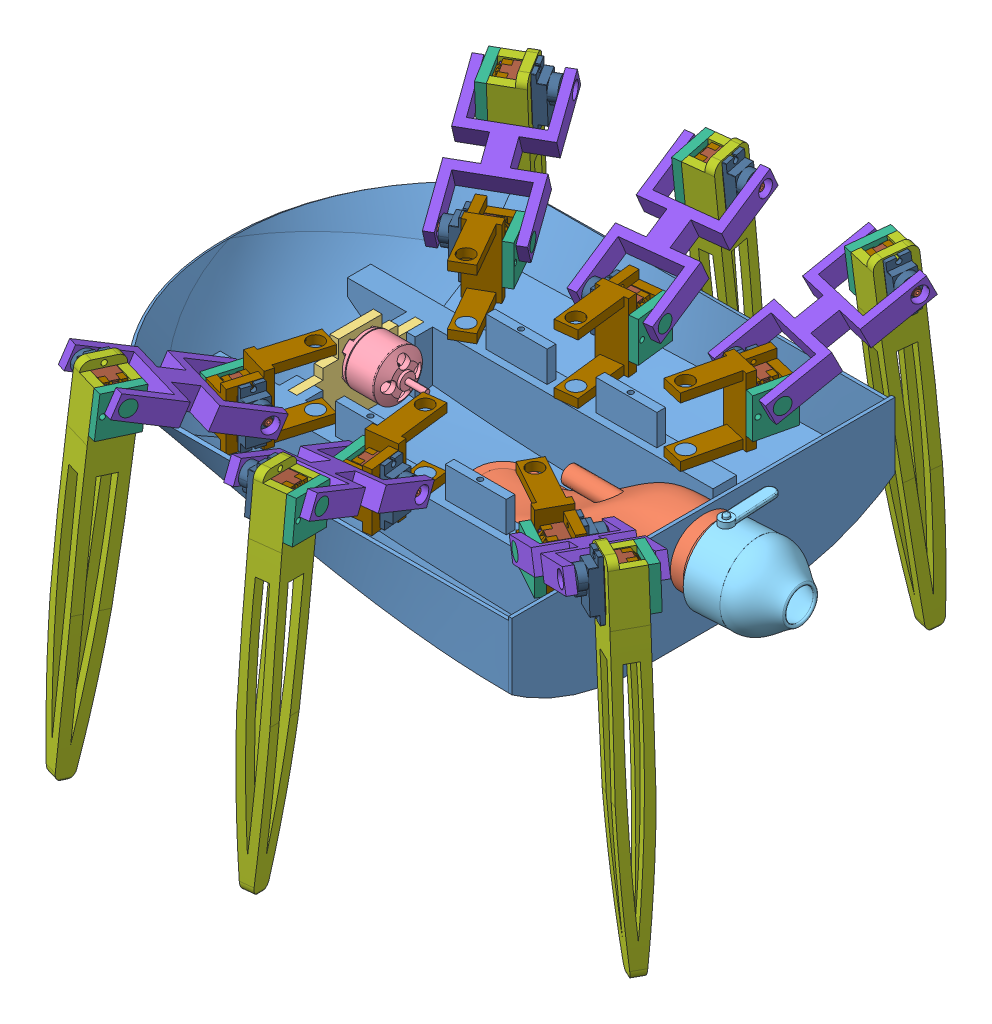
SolidWorks assembly TurbineCoverAssemble, configuration Default. Lengths in mm.
Overall size (353.16 206.26 356.62).
294 component instances, 27 part files, 17 mates.
Components (placement in the parent):
- BottonCover-1: BottonCover [Default] at (202.224 140.7704 163.9757) size (277.71 67.81 225.14)
- Turbine sketch-1: Turbine sketch [Default] at (187.224 85.7703 163.9757) x (0.000008 -1 0) z (1 0.000008 0) size (64 54 170.85)
- MotorBaseAssemble-1: MotorBaseAssemble [Default] at (-58.3893 121.5175 203.7657) x (0 -1 0) z (1 0 0) size (43.76 73 43.4)
  - motorBase-1: motorBase [Default] at (16.3885 39.79 60.6133) size (43.4 73 5)
  - Motor_BLDC_2212,6T_2200KV-1: Motor_BLDC_2212,6T_2200KV [Default] at (0.7745 39.79 64.0133) x (1 0 0) z (0 -1 0) size (27.9 40 27.9)
- Turbine Steering-2: Turbine Steering [Default] at (233.1876 119.5531 162.7395) x (-0.998386 -0.000008 0.056796) z (-0.056796 0 -0.998386) size (44.47 54 52.58)
- Leg assamble-1: Leg assamble [Default] at (-57.4595 156.272 55.9898) x (-0.493863 0.112847 -0.862186) z (0.867729 0 -0.497038) size (123.73 200 44.3)
  - CoverLeg-1: CoverLeg [Default] at (5.4977 12.0108 18.4868) size (22.4 22.9 10)
  - LowLeg-1: LowLeg [Default] at (5.4977 12.0108 35.7868) size (22.4 200 18.22)
  - JoinLeg-1: JoinLeg [Default] at (-21.7924 8.0579 35.6368) x (0 0 -1) z (0.947571 0.319544 0) size (44.3 12.4 85)
  - CoverLeg-3: CoverLeg [Default] at (-63.8885 -11.1546 52.7868) x (-0.993612 0.112847 0) z (0 0 -1) size (22.4 22.9 10)
  - MG90S-1: MG90S [Default] at (-15.7901 -20.7716 66.5373) x (1 0 0) z (0 -1 0) size (13.58 32.57 32)
    - MG90S.STEP-1: MG90S.STEP [Default] at origin size (13.58 32.57 32)
      - Part1.STEP-1: Part1.STEP [Default] at (21.0878 -43.0505 -32.5824) x (0 0 -1) z (1 0 0) size (22.54 9.07 12)
      - Part2.STEP-1: Part2.STEP [Default] at (21.0878 -25.5505 -32.5824) x (0 0 -1) z (1 0 0) size (32 13 12)
      - Part3.STEP-1: Part3.STEP [Default] at (21.0878 -36.0505 -32.5824) x (0 0 -1) z (1 0 0) size (22.5 16 12)
      - spur gear_iso_ISO - Spur gear 0.25M 38T 20PA 1.5FW ---S38A75H50L1.5N.STEP-1: spur gear_iso_ISO - Spur gear 0.25M 38T 20PA 1.5FW ---S38A75H50L1.5N.STEP [Default] at (21.0878 -22.3005 -37.8324) x (0 -1 0) z (0.87496 0 0.484196) size (1.5 9.98 10)
      - spur gear_iso_ISO - Spur gear 0.3M 31T 20PA 2FW ---S31A75H50L1.25N.STEP-1: spur gear_iso_ISO - Spur gear 0.3M 31T 20PA 2FW ---S31A75H50L1.25N.STEP [Default] at (21.0878 -19.8005 -31.3324) x (0 -1 0) z (0.109568 0 -0.993979) size (2 9.88 9.89)
      - spur gear_iso_ISO - Spur gear 0.4M 23T 20PA 2.75FW ---S23A75H50L1.5N.STEP-1: spur gear_iso_ISO - Spur gear 0.4M 23T 20PA 2.75FW ---S23A75H50L1.5N.STEP [Default] at (21.0878 -19.8005 -37.8324) x (0 1 0) z (-0.993238 0 0.116099) size (2.75 9.97 9.99)
      - spur gear_iso_ISO - Spur gear 0.25M 31T 20PA 1.25FW ---S31A75H50L1.25N.STEP-1: spur gear_iso_ISO - Spur gear 0.25M 31T 20PA 1.25FW ---S31A75H50L1.25N.STEP [Default] at (21.0878 -25.0505 -31.3324) x (0 1 0) z (0.977188 0 0.212376) size (1.25 8.24 8.25)
      - spur gear_iso_ISO - Spur gear 0.25M 10T 20PA 2FW ---S10A75H50L1.25N.STEP-1: spur gear_iso_ISO - Spur gear 0.25M 10T 20PA 2FW ---S10A75H50L1.25N.STEP [Default] at (21.0878 -23.8005 -31.3324) x (0 1 0) z (0.977188 0 0.212376) size (2 2.87 3)
      - gear3.STEP-1: gear3.STEP [Default] at (21.0878 -22.3005 -37.8324) x (0.87496 0 0.484196) z (-0.484196 0 0.87496) size (3.98 2.5 3.92)
      - gear1.STEP-1: gear1.STEP [Default] at (21.0878 -19.8005 -31.3324) x (0.109568 0 -0.993979) z (0.993979 0 0.109568) size (3.96 2.5 3.87)
      - gear2.STEP-1: gear2.STEP [Default] at (21.0878 -26.3005 -26.3324) x (0.891105 0 -0.453797) z (0.453797 0 0.891105) size (2.5 2.5 2.5)
      - Part4.STEP-1: Part4.STEP [Default] at (21.0878 -17.0505 -37.8324) x (0.993238 0 -0.116099) z (0.116099 0 0.993238) size (4.5 6.5 4.5)
      - Motor_Body.STEP-1: Motor_Body.STEP [Default] at (21.0878 -26.5505 -26.3324) x (-1 0 0) z (0 0 1) size (10 14.25 8)
      - Motor_Body2.STEP-1: Motor_Body2.STEP [Default] at (21.0878 -39.0505 -26.3324) size (10 2 8)
      - cilinder2.STEP-1: cilinder2.STEP [Default] at (21.0878 -31.8005 -37.8324) x (0.116099 0 0.993238) z (-0.993238 0 0.116099) size (1.5 15 1.5)
      - cilinder1.STEP-1: cilinder1.STEP [Default] at (21.0878 -27.3005 -31.3324) x (0.109568 0 -0.993979) z (0.993979 0 0.109568) size (1.25 12 1.25)
      - Part5.STEP-1: Part5.STEP [Default] at (21.0878 -40.0505 -32.0824) x (0 0 -1) z (1 0 0) size (19.28 16 10.15)
      - Part6.STEP-1: Part6.STEP [Default] at (16.5878 -42.0505 -22.8324) size (1.5 21 1.5)
      - Part6.STEP-2: Part6.STEP [Default] at (25.5878 -40.5505 -42.3324) size (1.5 21 1.5)
  - MG90S-2: MG90S [Default] at (-46.7884 -45.6872 4.9363) x (-0.993612 0.112847 0) z (-0.112847 -0.993612 0) size (13.58 32.57 32)
    - MG90S.STEP-1: MG90S.STEP [Default] at origin size (13.58 32.57 32)
      - Part1.STEP-1: Part1.STEP [Default] at (21.0878 -43.0505 -32.5824) x (0 0 -1) z (1 0 0) size (22.54 9.07 12)
      - Part2.STEP-1: Part2.STEP [Default] at (21.0878 -25.5505 -32.5824) x (0 0 -1) z (1 0 0) size (32 13 12)
      - Part3.STEP-1: Part3.STEP [Default] at (21.0878 -36.0505 -32.5824) x (0 0 -1) z (1 0 0) size (22.5 16 12)
      - spur gear_iso_ISO - Spur gear 0.25M 38T 20PA 1.5FW ---S38A75H50L1.5N.STEP-1: spur gear_iso_ISO - Spur gear 0.25M 38T 20PA 1.5FW ---S38A75H50L1.5N.STEP [Default] at (21.0878 -22.3005 -37.8324) x (0 -1 0) z (0.87496 0 0.484196) size (1.5 9.98 10)
      - spur gear_iso_ISO - Spur gear 0.3M 31T 20PA 2FW ---S31A75H50L1.25N.STEP-1: spur gear_iso_ISO - Spur gear 0.3M 31T 20PA 2FW ---S31A75H50L1.25N.STEP [Default] at (21.0878 -19.8005 -31.3324) x (0 -1 0) z (0.109568 0 -0.993979) size (2 9.88 9.89)
      - spur gear_iso_ISO - Spur gear 0.4M 23T 20PA 2.75FW ---S23A75H50L1.5N.STEP-1: spur gear_iso_ISO - Spur gear 0.4M 23T 20PA 2.75FW ---S23A75H50L1.5N.STEP [Default] at (21.0878 -19.8005 -37.8324) x (0 1 0) z (-0.993238 0 0.116099) size (2.75 9.97 9.99)
      - spur gear_iso_ISO - Spur gear 0.25M 31T 20PA 1.25FW ---S31A75H50L1.25N.STEP-1: spur gear_iso_ISO - Spur gear 0.25M 31T 20PA 1.25FW ---S31A75H50L1.25N.STEP [Default] at (21.0878 -25.0505 -31.3324) x (0 1 0) z (0.977188 0 0.212376) size (1.25 8.24 8.25)
      - spur gear_iso_ISO - Spur gear 0.25M 10T 20PA 2FW ---S10A75H50L1.25N.STEP-1: spur gear_iso_ISO - Spur gear 0.25M 10T 20PA 2FW ---S10A75H50L1.25N.STEP [Default] at (21.0878 -23.8005 -31.3324) x (0 1 0) z (0.977188 0 0.212376) size (2 2.87 3)
      - gear3.STEP-1: gear3.STEP [Default] at (21.0878 -22.3005 -37.8324) x (0.87496 0 0.484196) z (-0.484196 0 0.87496) size (3.98 2.5 3.92)
      - gear1.STEP-1: gear1.STEP [Default] at (21.0878 -19.8005 -31.3324) x (0.109568 0 -0.993979) z (0.993979 0 0.109568) size (3.96 2.5 3.87)
      - gear2.STEP-1: gear2.STEP [Default] at (21.0878 -26.3005 -26.3324) x (0.891105 0 -0.453797) z (0.453797 0 0.891105) size (2.5 2.5 2.5)
      - Part4.STEP-1: Part4.STEP [Default] at (21.0878 -17.0505 -37.8324) x (0.993238 0 -0.116099) z (0.116099 0 0.993238) size (4.5 6.5 4.5)
      - Motor_Body.STEP-1: Motor_Body.STEP [Default] at (21.0878 -26.5505 -26.3324) x (-1 0 0) z (0 0 1) size (10 14.25 8)
      - Motor_Body2.STEP-1: Motor_Body2.STEP [Default] at (21.0878 -39.0505 -26.3324) size (10 2 8)
      - cilinder2.STEP-1: cilinder2.STEP [Default] at (21.0878 -31.8005 -37.8324) x (0.116099 0 0.993238) z (-0.993238 0 0.116099) size (1.5 15 1.5)
      - cilinder1.STEP-1: cilinder1.STEP [Default] at (21.0878 -27.3005 -31.3324) x (0.109568 0 -0.993979) z (0.993979 0 0.109568) size (1.25 12 1.25)
      - Part5.STEP-1: Part5.STEP [Default] at (21.0878 -40.0505 -32.0824) x (0 0 -1) z (1 0 0) size (19.28 16 10.15)
      - Part6.STEP-1: Part6.STEP [Default] at (16.5878 -42.0505 -22.8324) size (1.5 21 1.5)
      - Part6.STEP-2: Part6.STEP [Default] at (25.5878 -40.5505 -42.3324) size (1.5 21 1.5)
  - JointChassis-4: JointChassis [Default] at (-63.8885 -11.1546 30.4868) x (-0.112847 -0.993612 0) z (0 0 1) size (39.1 52.4 17.3)
- Leg assamble-2: Leg assamble [Default] at (37.6165 156.272 28.8883) x (-0.115049 0.112847 -0.986929) z (0.993274 0 -0.115788) size (123.73 200 44.3)
  - CoverLeg-1: CoverLeg [Default] at (5.4977 12.0108 18.4868) size (22.4 22.9 10)
  - LowLeg-1: LowLeg [Default] at (5.4977 12.0108 35.7868) size (22.4 200 18.22)
  - JoinLeg-1: JoinLeg [Default] at (-21.7924 8.0579 35.6368) x (0 0 -1) z (0.947571 0.319544 0) size (44.3 12.4 85)
  - CoverLeg-3: CoverLeg [Default] at (-63.8885 -11.1546 52.7868) x (-0.993612 0.112847 0) z (0 0 -1) size (22.4 22.9 10)
  - MG90S-1: MG90S [Default] at (-15.7901 -20.7716 66.5373) x (1 0 0) z (0 -1 0) size (13.58 32.57 32)
    - MG90S.STEP-1: MG90S.STEP [Default] at origin size (13.58 32.57 32)
      - Part1.STEP-1: Part1.STEP [Default] at (21.0878 -43.0505 -32.5824) x (0 0 -1) z (1 0 0) size (22.54 9.07 12)
      - Part2.STEP-1: Part2.STEP [Default] at (21.0878 -25.5505 -32.5824) x (0 0 -1) z (1 0 0) size (32 13 12)
      - Part3.STEP-1: Part3.STEP [Default] at (21.0878 -36.0505 -32.5824) x (0 0 -1) z (1 0 0) size (22.5 16 12)
      - spur gear_iso_ISO - Spur gear 0.25M 38T 20PA 1.5FW ---S38A75H50L1.5N.STEP-1: spur gear_iso_ISO - Spur gear 0.25M 38T 20PA 1.5FW ---S38A75H50L1.5N.STEP [Default] at (21.0878 -22.3005 -37.8324) x (0 -1 0) z (0.87496 0 0.484196) size (1.5 9.98 10)
      - spur gear_iso_ISO - Spur gear 0.3M 31T 20PA 2FW ---S31A75H50L1.25N.STEP-1: spur gear_iso_ISO - Spur gear 0.3M 31T 20PA 2FW ---S31A75H50L1.25N.STEP [Default] at (21.0878 -19.8005 -31.3324) x (0 -1 0) z (0.109568 0 -0.993979) size (2 9.88 9.89)
      - spur gear_iso_ISO - Spur gear 0.4M 23T 20PA 2.75FW ---S23A75H50L1.5N.STEP-1: spur gear_iso_ISO - Spur gear 0.4M 23T 20PA 2.75FW ---S23A75H50L1.5N.STEP [Default] at (21.0878 -19.8005 -37.8324) x (0 1 0) z (-0.993238 0 0.116099) size (2.75 9.97 9.99)
      - spur gear_iso_ISO - Spur gear 0.25M 31T 20PA 1.25FW ---S31A75H50L1.25N.STEP-1: spur gear_iso_ISO - Spur gear 0.25M 31T 20PA 1.25FW ---S31A75H50L1.25N.STEP [Default] at (21.0878 -25.0505 -31.3324) x (0 1 0) z (0.977188 0 0.212376) size (1.25 8.24 8.25)
      - spur gear_iso_ISO - Spur gear 0.25M 10T 20PA 2FW ---S10A75H50L1.25N.STEP-1: spur gear_iso_ISO - Spur gear 0.25M 10T 20PA 2FW ---S10A75H50L1.25N.STEP [Default] at (21.0878 -23.8005 -31.3324) x (0 1 0) z (0.977188 0 0.212376) size (2 2.87 3)
      - gear3.STEP-1: gear3.STEP [Default] at (21.0878 -22.3005 -37.8324) x (0.87496 0 0.484196) z (-0.484196 0 0.87496) size (3.98 2.5 3.92)
      - gear1.STEP-1: gear1.STEP [Default] at (21.0878 -19.8005 -31.3324) x (0.109568 0 -0.993979) z (0.993979 0 0.109568) size (3.96 2.5 3.87)
      - gear2.STEP-1: gear2.STEP [Default] at (21.0878 -26.3005 -26.3324) x (0.891105 0 -0.453797) z (0.453797 0 0.891105) size (2.5 2.5 2.5)
      - Part4.STEP-1: Part4.STEP [Default] at (21.0878 -17.0505 -37.8324) x (0.993238 0 -0.116099) z (0.116099 0 0.993238) size (4.5 6.5 4.5)
      - Motor_Body.STEP-1: Motor_Body.STEP [Default] at (21.0878 -26.5505 -26.3324) x (-1 0 0) z (0 0 1) size (10 14.25 8)
      - Motor_Body2.STEP-1: Motor_Body2.STEP [Default] at (21.0878 -39.0505 -26.3324) size (10 2 8)
      - cilinder2.STEP-1: cilinder2.STEP [Default] at (21.0878 -31.8005 -37.8324) x (0.116099 0 0.993238) z (-0.993238 0 0.116099) size (1.5 15 1.5)
      - cilinder1.STEP-1: cilinder1.STEP [Default] at (21.0878 -27.3005 -31.3324) x (0.109568 0 -0.993979) z (0.993979 0 0.109568) size (1.25 12 1.25)
      - Part5.STEP-1: Part5.STEP [Default] at (21.0878 -40.0505 -32.0824) x (0 0 -1) z (1 0 0) size (19.28 16 10.15)
      - Part6.STEP-1: Part6.STEP [Default] at (16.5878 -42.0505 -22.8324) size (1.5 21 1.5)
      - Part6.STEP-2: Part6.STEP [Default] at (25.5878 -40.5505 -42.3324) size (1.5 21 1.5)
  - MG90S-2: MG90S [Default] at (-46.7884 -45.6872 4.9363) x (-0.993612 0.112847 0) z (-0.112847 -0.993612 0) size (13.58 32.57 32)
    - MG90S.STEP-1: MG90S.STEP [Default] at origin size (13.58 32.57 32)
      - Part1.STEP-1: Part1.STEP [Default] at (21.0878 -43.0505 -32.5824) x (0 0 -1) z (1 0 0) size (22.54 9.07 12)
      - Part2.STEP-1: Part2.STEP [Default] at (21.0878 -25.5505 -32.5824) x (0 0 -1) z (1 0 0) size (32 13 12)
      - Part3.STEP-1: Part3.STEP [Default] at (21.0878 -36.0505 -32.5824) x (0 0 -1) z (1 0 0) size (22.5 16 12)
      - spur gear_iso_ISO - Spur gear 0.25M 38T 20PA 1.5FW ---S38A75H50L1.5N.STEP-1: spur gear_iso_ISO - Spur gear 0.25M 38T 20PA 1.5FW ---S38A75H50L1.5N.STEP [Default] at (21.0878 -22.3005 -37.8324) x (0 -1 0) z (0.87496 0 0.484196) size (1.5 9.98 10)
      - spur gear_iso_ISO - Spur gear 0.3M 31T 20PA 2FW ---S31A75H50L1.25N.STEP-1: spur gear_iso_ISO - Spur gear 0.3M 31T 20PA 2FW ---S31A75H50L1.25N.STEP [Default] at (21.0878 -19.8005 -31.3324) x (0 -1 0) z (0.109568 0 -0.993979) size (2 9.88 9.89)
      - spur gear_iso_ISO - Spur gear 0.4M 23T 20PA 2.75FW ---S23A75H50L1.5N.STEP-1: spur gear_iso_ISO - Spur gear 0.4M 23T 20PA 2.75FW ---S23A75H50L1.5N.STEP [Default] at (21.0878 -19.8005 -37.8324) x (0 1 0) z (-0.993238 0 0.116099) size (2.75 9.97 9.99)
      - spur gear_iso_ISO - Spur gear 0.25M 31T 20PA 1.25FW ---S31A75H50L1.25N.STEP-1: spur gear_iso_ISO - Spur gear 0.25M 31T 20PA 1.25FW ---S31A75H50L1.25N.STEP [Default] at (21.0878 -25.0505 -31.3324) x (0 1 0) z (0.977188 0 0.212376) size (1.25 8.24 8.25)
      - spur gear_iso_ISO - Spur gear 0.25M 10T 20PA 2FW ---S10A75H50L1.25N.STEP-1: spur gear_iso_ISO - Spur gear 0.25M 10T 20PA 2FW ---S10A75H50L1.25N.STEP [Default] at (21.0878 -23.8005 -31.3324) x (0 1 0) z (0.977188 0 0.212376) size (2 2.87 3)
      - gear3.STEP-1: gear3.STEP [Default] at (21.0878 -22.3005 -37.8324) x (0.87496 0 0.484196) z (-0.484196 0 0.87496) size (3.98 2.5 3.92)
      - gear1.STEP-1: gear1.STEP [Default] at (21.0878 -19.8005 -31.3324) x (0.109568 0 -0.993979) z (0.993979 0 0.109568) size (3.96 2.5 3.87)
      - gear2.STEP-1: gear2.STEP [Default] at (21.0878 -26.3005 -26.3324) x (0.891105 0 -0.453797) z (0.453797 0 0.891105) size (2.5 2.5 2.5)
      - Part4.STEP-1: Part4.STEP [Default] at (21.0878 -17.0505 -37.8324) x (0.993238 0 -0.116099) z (0.116099 0 0.993238) size (4.5 6.5 4.5)
      - Motor_Body.STEP-1: Motor_Body.STEP [Default] at (21.0878 -26.5505 -26.3324) x (-1 0 0) z (0 0 1) size (10 14.25 8)
      - Motor_Body2.STEP-1: Motor_Body2.STEP [Default] at (21.0878 -39.0505 -26.3324) size (10 2 8)
      - cilinder2.STEP-1: cilinder2.STEP [Default] at (21.0878 -31.8005 -37.8324) x (0.116099 0 0.993238) z (-0.993238 0 0.116099) size (1.5 15 1.5)
      - cilinder1.STEP-1: cilinder1.STEP [Default] at (21.0878 -27.3005 -31.3324) x (0.109568 0 -0.993979) z (0.993979 0 0.109568) size (1.25 12 1.25)
      - Part5.STEP-1: Part5.STEP [Default] at (21.0878 -40.0505 -32.0824) x (0 0 -1) z (1 0 0) size (19.28 16 10.15)
      - Part6.STEP-1: Part6.STEP [Default] at (16.5878 -42.0505 -22.8324) size (1.5 21 1.5)
      - Part6.STEP-2: Part6.STEP [Default] at (25.5878 -40.5505 -42.3324) size (1.5 21 1.5)
  - JointChassis-4: JointChassis [Default] at (-63.8885 -11.1546 30.4868) x (-0.112847 -0.993612 0) z (0 0 1) size (39.1 52.4 17.3)
- Leg assamble-3: Leg assamble [Default] at (134.6264 156.272 17.3538) x (0.22549 0.112847 -0.967688) z (0.973909 0 0.226939) size (123.73 200 44.3)
  - CoverLeg-1: CoverLeg [Default] at (5.4977 12.0108 18.4868) size (22.4 22.9 10)
  - LowLeg-1: LowLeg [Default] at (5.4977 12.0108 35.7868) size (22.4 200 18.22)
  - JoinLeg-1: JoinLeg [Default] at (-21.7924 8.0579 35.6368) x (0 0 -1) z (0.947571 0.319544 0) size (44.3 12.4 85)
  - CoverLeg-3: CoverLeg [Default] at (-63.8885 -11.1546 52.7868) x (-0.993612 0.112847 0) z (0 0 -1) size (22.4 22.9 10)
  - MG90S-1: MG90S [Default] at (-15.7901 -20.7716 66.5373) x (1 0 0) z (0 -1 0) size (13.58 32.57 32)
    - MG90S.STEP-1: MG90S.STEP [Default] at origin size (13.58 32.57 32)
      - Part1.STEP-1: Part1.STEP [Default] at (21.0878 -43.0505 -32.5824) x (0 0 -1) z (1 0 0) size (22.54 9.07 12)
      - Part2.STEP-1: Part2.STEP [Default] at (21.0878 -25.5505 -32.5824) x (0 0 -1) z (1 0 0) size (32 13 12)
      - Part3.STEP-1: Part3.STEP [Default] at (21.0878 -36.0505 -32.5824) x (0 0 -1) z (1 0 0) size (22.5 16 12)
      - spur gear_iso_ISO - Spur gear 0.25M 38T 20PA 1.5FW ---S38A75H50L1.5N.STEP-1: spur gear_iso_ISO - Spur gear 0.25M 38T 20PA 1.5FW ---S38A75H50L1.5N.STEP [Default] at (21.0878 -22.3005 -37.8324) x (0 -1 0) z (0.87496 0 0.484196) size (1.5 9.98 10)
      - spur gear_iso_ISO - Spur gear 0.3M 31T 20PA 2FW ---S31A75H50L1.25N.STEP-1: spur gear_iso_ISO - Spur gear 0.3M 31T 20PA 2FW ---S31A75H50L1.25N.STEP [Default] at (21.0878 -19.8005 -31.3324) x (0 -1 0) z (0.109568 0 -0.993979) size (2 9.88 9.89)
      - spur gear_iso_ISO - Spur gear 0.4M 23T 20PA 2.75FW ---S23A75H50L1.5N.STEP-1: spur gear_iso_ISO - Spur gear 0.4M 23T 20PA 2.75FW ---S23A75H50L1.5N.STEP [Default] at (21.0878 -19.8005 -37.8324) x (0 1 0) z (-0.993238 0 0.116099) size (2.75 9.97 9.99)
      - spur gear_iso_ISO - Spur gear 0.25M 31T 20PA 1.25FW ---S31A75H50L1.25N.STEP-1: spur gear_iso_ISO - Spur gear 0.25M 31T 20PA 1.25FW ---S31A75H50L1.25N.STEP [Default] at (21.0878 -25.0505 -31.3324) x (0 1 0) z (0.977188 0 0.212376) size (1.25 8.24 8.25)
      - spur gear_iso_ISO - Spur gear 0.25M 10T 20PA 2FW ---S10A75H50L1.25N.STEP-1: spur gear_iso_ISO - Spur gear 0.25M 10T 20PA 2FW ---S10A75H50L1.25N.STEP [Default] at (21.0878 -23.8005 -31.3324) x (0 1 0) z (0.977188 0 0.212376) size (2 2.87 3)
      - gear3.STEP-1: gear3.STEP [Default] at (21.0878 -22.3005 -37.8324) x (0.87496 0 0.484196) z (-0.484196 0 0.87496) size (3.98 2.5 3.92)
      - gear1.STEP-1: gear1.STEP [Default] at (21.0878 -19.8005 -31.3324) x (0.109568 0 -0.993979) z (0.993979 0 0.109568) size (3.96 2.5 3.87)
      - gear2.STEP-1: gear2.STEP [Default] at (21.0878 -26.3005 -26.3324) x (0.891105 0 -0.453797) z (0.453797 0 0.891105) size (2.5 2.5 2.5)
      - Part4.STEP-1: Part4.STEP [Default] at (21.0878 -17.0505 -37.8324) x (0.993238 0 -0.116099) z (0.116099 0 0.993238) size (4.5 6.5 4.5)
      - Motor_Body.STEP-1: Motor_Body.STEP [Default] at (21.0878 -26.5505 -26.3324) x (-1 0 0) z (0 0 1) size (10 14.25 8)
      - Motor_Body2.STEP-1: Motor_Body2.STEP [Default] at (21.0878 -39.0505 -26.3324) size (10 2 8)
      - cilinder2.STEP-1: cilinder2.STEP [Default] at (21.0878 -31.8005 -37.8324) x (0.116099 0 0.993238) z (-0.993238 0 0.116099) size (1.5 15 1.5)
      - cilinder1.STEP-1: cilinder1.STEP [Default] at (21.0878 -27.3005 -31.3324) x (0.109568 0 -0.993979) z (0.993979 0 0.109568) size (1.25 12 1.25)
      - Part5.STEP-1: Part5.STEP [Default] at (21.0878 -40.0505 -32.0824) x (0 0 -1) z (1 0 0) size (19.28 16 10.15)
      - Part6.STEP-1: Part6.STEP [Default] at (16.5878 -42.0505 -22.8324) size (1.5 21 1.5)
      - Part6.STEP-2: Part6.STEP [Default] at (25.5878 -40.5505 -42.3324) size (1.5 21 1.5)
  - MG90S-2: MG90S [Default] at (-46.7884 -45.6872 4.9363) x (-0.993612 0.112847 0) z (-0.112847 -0.993612 0) size (13.58 32.57 32)
    - MG90S.STEP-1: MG90S.STEP [Default] at origin size (13.58 32.57 32)
      - Part1.STEP-1: Part1.STEP [Default] at (21.0878 -43.0505 -32.5824) x (0 0 -1) z (1 0 0) size (22.54 9.07 12)
      - Part2.STEP-1: Part2.STEP [Default] at (21.0878 -25.5505 -32.5824) x (0 0 -1) z (1 0 0) size (32 13 12)
      - Part3.STEP-1: Part3.STEP [Default] at (21.0878 -36.0505 -32.5824) x (0 0 -1) z (1 0 0) size (22.5 16 12)
      - spur gear_iso_ISO - Spur gear 0.25M 38T 20PA 1.5FW ---S38A75H50L1.5N.STEP-1: spur gear_iso_ISO - Spur gear 0.25M 38T 20PA 1.5FW ---S38A75H50L1.5N.STEP [Default] at (21.0878 -22.3005 -37.8324) x (0 -1 0) z (0.87496 0 0.484196) size (1.5 9.98 10)
      - spur gear_iso_ISO - Spur gear 0.3M 31T 20PA 2FW ---S31A75H50L1.25N.STEP-1: spur gear_iso_ISO - Spur gear 0.3M 31T 20PA 2FW ---S31A75H50L1.25N.STEP [Default] at (21.0878 -19.8005 -31.3324) x (0 -1 0) z (0.109568 0 -0.993979) size (2 9.88 9.89)
      - spur gear_iso_ISO - Spur gear 0.4M 23T 20PA 2.75FW ---S23A75H50L1.5N.STEP-1: spur gear_iso_ISO - Spur gear 0.4M 23T 20PA 2.75FW ---S23A75H50L1.5N.STEP [Default] at (21.0878 -19.8005 -37.8324) x (0 1 0) z (-0.993238 0 0.116099) size (2.75 9.97 9.99)
      - spur gear_iso_ISO - Spur gear 0.25M 31T 20PA 1.25FW ---S31A75H50L1.25N.STEP-1: spur gear_iso_ISO - Spur gear 0.25M 31T 20PA 1.25FW ---S31A75H50L1.25N.STEP [Default] at (21.0878 -25.0505 -31.3324) x (0 1 0) z (0.977188 0 0.212376) size (1.25 8.24 8.25)
      - spur gear_iso_ISO - Spur gear 0.25M 10T 20PA 2FW ---S10A75H50L1.25N.STEP-1: spur gear_iso_ISO - Spur gear 0.25M 10T 20PA 2FW ---S10A75H50L1.25N.STEP [Default] at (21.0878 -23.8005 -31.3324) x (0 1 0) z (0.977188 0 0.212376) size (2 2.87 3)
      - gear3.STEP-1: gear3.STEP [Default] at (21.0878 -22.3005 -37.8324) x (0.87496 0 0.484196) z (-0.484196 0 0.87496) size (3.98 2.5 3.92)
      - gear1.STEP-1: gear1.STEP [Default] at (21.0878 -19.8005 -31.3324) x (0.109568 0 -0.993979) z (0.993979 0 0.109568) size (3.96 2.5 3.87)
      - gear2.STEP-1: gear2.STEP [Default] at (21.0878 -26.3005 -26.3324) x (0.891105 0 -0.453797) z (0.453797 0 0.891105) size (2.5 2.5 2.5)
      - Part4.STEP-1: Part4.STEP [Default] at (21.0878 -17.0505 -37.8324) x (0.993238 0 -0.116099) z (0.116099 0 0.993238) size (4.5 6.5 4.5)
      - Motor_Body.STEP-1: Motor_Body.STEP [Default] at (21.0878 -26.5505 -26.3324) x (-1 0 0) z (0 0 1) size (10 14.25 8)
      - Motor_Body2.STEP-1: Motor_Body2.STEP [Default] at (21.0878 -39.0505 -26.3324) size (10 2 8)
      - cilinder2.STEP-1: cilinder2.STEP [Default] at (21.0878 -31.8005 -37.8324) x (0.116099 0 0.993238) z (-0.993238 0 0.116099) size (1.5 15 1.5)
      - cilinder1.STEP-1: cilinder1.STEP [Default] at (21.0878 -27.3005 -31.3324) x (0.109568 0 -0.993979) z (0.993979 0 0.109568) size (1.25 12 1.25)
      - Part5.STEP-1: Part5.STEP [Default] at (21.0878 -40.0505 -32.0824) x (0 0 -1) z (1 0 0) size (19.28 16 10.15)
      - Part6.STEP-1: Part6.STEP [Default] at (16.5878 -42.0505 -22.8324) size (1.5 21 1.5)
      - Part6.STEP-2: Part6.STEP [Default] at (25.5878 -40.5505 -42.3324) size (1.5 21 1.5)
  - JointChassis-4: JointChassis [Default] at (-63.8885 -11.1546 30.4868) x (-0.112847 -0.993612 0) z (0 0 1) size (39.1 52.4 17.3)
- Leg assamble-4: Leg assamble [Default] at (254.6194 156.272 219.4987) x (0.871499 0.112847 0.477237) z (-0.480305 0 0.877102) size (123.73 200 44.3)
  - CoverLeg-1: CoverLeg [Default] at (5.4977 12.0108 18.4868) size (22.4 22.9 10)
  - LowLeg-1: LowLeg [Default] at (5.4977 12.0108 35.7868) size (22.4 200 18.22)
  - JoinLeg-1: JoinLeg [Default] at (-21.7924 8.0579 35.6368) x (0 0 -1) z (0.947571 0.319544 0) size (44.3 12.4 85)
  - CoverLeg-3: CoverLeg [Default] at (-63.8885 -11.1546 52.7868) x (-0.993612 0.112847 0) z (0 0 -1) size (22.4 22.9 10)
  - MG90S-1: MG90S [Default] at (-15.7901 -20.7716 66.5373) x (1 0 0) z (0 -1 0) size (13.58 32.57 32)
    - MG90S.STEP-1: MG90S.STEP [Default] at origin size (13.58 32.57 32)
      - Part1.STEP-1: Part1.STEP [Default] at (21.0878 -43.0505 -32.5824) x (0 0 -1) z (1 0 0) size (22.54 9.07 12)
      - Part2.STEP-1: Part2.STEP [Default] at (21.0878 -25.5505 -32.5824) x (0 0 -1) z (1 0 0) size (32 13 12)
      - Part3.STEP-1: Part3.STEP [Default] at (21.0878 -36.0505 -32.5824) x (0 0 -1) z (1 0 0) size (22.5 16 12)
      - spur gear_iso_ISO - Spur gear 0.25M 38T 20PA 1.5FW ---S38A75H50L1.5N.STEP-1: spur gear_iso_ISO - Spur gear 0.25M 38T 20PA 1.5FW ---S38A75H50L1.5N.STEP [Default] at (21.0878 -22.3005 -37.8324) x (0 -1 0) z (0.87496 0 0.484196) size (1.5 9.98 10)
      - spur gear_iso_ISO - Spur gear 0.3M 31T 20PA 2FW ---S31A75H50L1.25N.STEP-1: spur gear_iso_ISO - Spur gear 0.3M 31T 20PA 2FW ---S31A75H50L1.25N.STEP [Default] at (21.0878 -19.8005 -31.3324) x (0 -1 0) z (0.109568 0 -0.993979) size (2 9.88 9.89)
      - spur gear_iso_ISO - Spur gear 0.4M 23T 20PA 2.75FW ---S23A75H50L1.5N.STEP-1: spur gear_iso_ISO - Spur gear 0.4M 23T 20PA 2.75FW ---S23A75H50L1.5N.STEP [Default] at (21.0878 -19.8005 -37.8324) x (0 1 0) z (-0.993238 0 0.116099) size (2.75 9.97 9.99)
      - spur gear_iso_ISO - Spur gear 0.25M 31T 20PA 1.25FW ---S31A75H50L1.25N.STEP-1: spur gear_iso_ISO - Spur gear 0.25M 31T 20PA 1.25FW ---S31A75H50L1.25N.STEP [Default] at (21.0878 -25.0505 -31.3324) x (0 1 0) z (0.977188 0 0.212376) size (1.25 8.24 8.25)
      - spur gear_iso_ISO - Spur gear 0.25M 10T 20PA 2FW ---S10A75H50L1.25N.STEP-1: spur gear_iso_ISO - Spur gear 0.25M 10T 20PA 2FW ---S10A75H50L1.25N.STEP [Default] at (21.0878 -23.8005 -31.3324) x (0 1 0) z (0.977188 0 0.212376) size (2 2.87 3)
      - gear3.STEP-1: gear3.STEP [Default] at (21.0878 -22.3005 -37.8324) x (0.87496 0 0.484196) z (-0.484196 0 0.87496) size (3.98 2.5 3.92)
      - gear1.STEP-1: gear1.STEP [Default] at (21.0878 -19.8005 -31.3324) x (0.109568 0 -0.993979) z (0.993979 0 0.109568) size (3.96 2.5 3.87)
      - gear2.STEP-1: gear2.STEP [Default] at (21.0878 -26.3005 -26.3324) x (0.891105 0 -0.453797) z (0.453797 0 0.891105) size (2.5 2.5 2.5)
      - Part4.STEP-1: Part4.STEP [Default] at (21.0878 -17.0505 -37.8324) x (0.993238 0 -0.116099) z (0.116099 0 0.993238) size (4.5 6.5 4.5)
      - Motor_Body.STEP-1: Motor_Body.STEP [Default] at (21.0878 -26.5505 -26.3324) x (-1 0 0) z (0 0 1) size (10 14.25 8)
      - Motor_Body2.STEP-1: Motor_Body2.STEP [Default] at (21.0878 -39.0505 -26.3324) size (10 2 8)
      - cilinder2.STEP-1: cilinder2.STEP [Default] at (21.0878 -31.8005 -37.8324) x (0.116099 0 0.993238) z (-0.993238 0 0.116099) size (1.5 15 1.5)
      - cilinder1.STEP-1: cilinder1.STEP [Default] at (21.0878 -27.3005 -31.3324) x (0.109568 0 -0.993979) z (0.993979 0 0.109568) size (1.25 12 1.25)
      - Part5.STEP-1: Part5.STEP [Default] at (21.0878 -40.0505 -32.0824) x (0 0 -1) z (1 0 0) size (19.28 16 10.15)
      - Part6.STEP-1: Part6.STEP [Default] at (16.5878 -42.0505 -22.8324) size (1.5 21 1.5)
      - Part6.STEP-2: Part6.STEP [Default] at (25.5878 -40.5505 -42.3324) size (1.5 21 1.5)
  - MG90S-2: MG90S [Default] at (-46.7884 -45.6872 4.9363) x (-0.993612 0.112847 0) z (-0.112847 -0.993612 0) size (13.58 32.57 32)
    - MG90S.STEP-1: MG90S.STEP [Default] at origin size (13.58 32.57 32)
      - Part1.STEP-1: Part1.STEP [Default] at (21.0878 -43.0505 -32.5824) x (0 0 -1) z (1 0 0) size (22.54 9.07 12)
      - Part2.STEP-1: Part2.STEP [Default] at (21.0878 -25.5505 -32.5824) x (0 0 -1) z (1 0 0) size (32 13 12)
      - Part3.STEP-1: Part3.STEP [Default] at (21.0878 -36.0505 -32.5824) x (0 0 -1) z (1 0 0) size (22.5 16 12)
      - spur gear_iso_ISO - Spur gear 0.25M 38T 20PA 1.5FW ---S38A75H50L1.5N.STEP-1: spur gear_iso_ISO - Spur gear 0.25M 38T 20PA 1.5FW ---S38A75H50L1.5N.STEP [Default] at (21.0878 -22.3005 -37.8324) x (0 -1 0) z (0.87496 0 0.484196) size (1.5 9.98 10)
      - spur gear_iso_ISO - Spur gear 0.3M 31T 20PA 2FW ---S31A75H50L1.25N.STEP-1: spur gear_iso_ISO - Spur gear 0.3M 31T 20PA 2FW ---S31A75H50L1.25N.STEP [Default] at (21.0878 -19.8005 -31.3324) x (0 -1 0) z (0.109568 0 -0.993979) size (2 9.88 9.89)
      - spur gear_iso_ISO - Spur gear 0.4M 23T 20PA 2.75FW ---S23A75H50L1.5N.STEP-1: spur gear_iso_ISO - Spur gear 0.4M 23T 20PA 2.75FW ---S23A75H50L1.5N.STEP [Default] at (21.0878 -19.8005 -37.8324) x (0 1 0) z (-0.993238 0 0.116099) size (2.75 9.97 9.99)
      - spur gear_iso_ISO - Spur gear 0.25M 31T 20PA 1.25FW ---S31A75H50L1.25N.STEP-1: spur gear_iso_ISO - Spur gear 0.25M 31T 20PA 1.25FW ---S31A75H50L1.25N.STEP [Default] at (21.0878 -25.0505 -31.3324) x (0 1 0) z (0.977188 0 0.212376) size (1.25 8.24 8.25)
      - spur gear_iso_ISO - Spur gear 0.25M 10T 20PA 2FW ---S10A75H50L1.25N.STEP-1: spur gear_iso_ISO - Spur gear 0.25M 10T 20PA 2FW ---S10A75H50L1.25N.STEP [Default] at (21.0878 -23.8005 -31.3324) x (0 1 0) z (0.977188 0 0.212376) size (2 2.87 3)
      - gear3.STEP-1: gear3.STEP [Default] at (21.0878 -22.3005 -37.8324) x (0.87496 0 0.484196) z (-0.484196 0 0.87496) size (3.98 2.5 3.92)
      - gear1.STEP-1: gear1.STEP [Default] at (21.0878 -19.8005 -31.3324) x (0.109568 0 -0.993979) z (0.993979 0 0.109568) size (3.96 2.5 3.87)
      - gear2.STEP-1: gear2.STEP [Default] at (21.0878 -26.3005 -26.3324) x (0.891105 0 -0.453797) z (0.453797 0 0.891105) size (2.5 2.5 2.5)
      - Part4.STEP-1: Part4.STEP [Default] at (21.0878 -17.0505 -37.8324) x (0.993238 0 -0.116099) z (0.116099 0 0.993238) size (4.5 6.5 4.5)
      - Motor_Body.STEP-1: Motor_Body.STEP [Default] at (21.0878 -26.5505 -26.3324) x (-1 0 0) z (0 0 1) size (10 14.25 8)
      - Motor_Body2.STEP-1: Motor_Body2.STEP [Default] at (21.0878 -39.0505 -26.3324) size (10 2 8)
      - cilinder2.STEP-1: cilinder2.STEP [Default] at (21.0878 -31.8005 -37.8324) x (0.116099 0 0.993238) z (-0.993238 0 0.116099) size (1.5 15 1.5)
      - cilinder1.STEP-1: cilinder1.STEP [Default] at (21.0878 -27.3005 -31.3324) x (0.109568 0 -0.993979) z (0.993979 0 0.109568) size (1.25 12 1.25)
      - Part5.STEP-1: Part5.STEP [Default] at (21.0878 -40.0505 -32.0824) x (0 0 -1) z (1 0 0) size (19.28 16 10.15)
      - Part6.STEP-1: Part6.STEP [Default] at (16.5878 -42.0505 -22.8324) size (1.5 21 1.5)
      - Part6.STEP-2: Part6.STEP [Default] at (25.5878 -40.5505 -42.3324) size (1.5 21 1.5)
  - JointChassis-4: JointChassis [Default] at (-63.8885 -11.1546 30.4868) x (-0.112847 -0.993612 0) z (0 0 1) size (39.1 52.4 17.3)
- Leg assamble-5: Leg assamble [Default] at (138.126 156.272 298.9018) x (0.118215 0.112847 0.986555) z (-0.992897 0 0.118975) size (123.73 200 44.3)
  - CoverLeg-1: CoverLeg [Default] at (5.4977 12.0108 18.4868) size (22.4 22.9 10)
  - LowLeg-1: LowLeg [Default] at (5.4977 12.0108 35.7868) size (22.4 200 18.22)
  - JoinLeg-1: JoinLeg [Default] at (-21.7924 8.0579 35.6368) x (0 0 -1) z (0.947571 0.319544 0) size (44.3 12.4 85)
  - CoverLeg-3: CoverLeg [Default] at (-63.8885 -11.1546 52.7868) x (-0.993612 0.112847 0) z (0 0 -1) size (22.4 22.9 10)
  - MG90S-1: MG90S [Default] at (-15.7901 -20.7716 66.5373) x (1 0 0) z (0 -1 0) size (13.58 32.57 32)
    - MG90S.STEP-1: MG90S.STEP [Default] at origin size (13.58 32.57 32)
      - Part1.STEP-1: Part1.STEP [Default] at (21.0878 -43.0505 -32.5824) x (0 0 -1) z (1 0 0) size (22.54 9.07 12)
      - Part2.STEP-1: Part2.STEP [Default] at (21.0878 -25.5505 -32.5824) x (0 0 -1) z (1 0 0) size (32 13 12)
      - Part3.STEP-1: Part3.STEP [Default] at (21.0878 -36.0505 -32.5824) x (0 0 -1) z (1 0 0) size (22.5 16 12)
      - spur gear_iso_ISO - Spur gear 0.25M 38T 20PA 1.5FW ---S38A75H50L1.5N.STEP-1: spur gear_iso_ISO - Spur gear 0.25M 38T 20PA 1.5FW ---S38A75H50L1.5N.STEP [Default] at (21.0878 -22.3005 -37.8324) x (0 -1 0) z (0.87496 0 0.484196) size (1.5 9.98 10)
      - spur gear_iso_ISO - Spur gear 0.3M 31T 20PA 2FW ---S31A75H50L1.25N.STEP-1: spur gear_iso_ISO - Spur gear 0.3M 31T 20PA 2FW ---S31A75H50L1.25N.STEP [Default] at (21.0878 -19.8005 -31.3324) x (0 -1 0) z (0.109568 0 -0.993979) size (2 9.88 9.89)
      - spur gear_iso_ISO - Spur gear 0.4M 23T 20PA 2.75FW ---S23A75H50L1.5N.STEP-1: spur gear_iso_ISO - Spur gear 0.4M 23T 20PA 2.75FW ---S23A75H50L1.5N.STEP [Default] at (21.0878 -19.8005 -37.8324) x (0 1 0) z (-0.993238 0 0.116099) size (2.75 9.97 9.99)
      - spur gear_iso_ISO - Spur gear 0.25M 31T 20PA 1.25FW ---S31A75H50L1.25N.STEP-1: spur gear_iso_ISO - Spur gear 0.25M 31T 20PA 1.25FW ---S31A75H50L1.25N.STEP [Default] at (21.0878 -25.0505 -31.3324) x (0 1 0) z (0.977188 0 0.212376) size (1.25 8.24 8.25)
      - spur gear_iso_ISO - Spur gear 0.25M 10T 20PA 2FW ---S10A75H50L1.25N.STEP-1: spur gear_iso_ISO - Spur gear 0.25M 10T 20PA 2FW ---S10A75H50L1.25N.STEP [Default] at (21.0878 -23.8005 -31.3324) x (0 1 0) z (0.977188 0 0.212376) size (2 2.87 3)
      - gear3.STEP-1: gear3.STEP [Default] at (21.0878 -22.3005 -37.8324) x (0.87496 0 0.484196) z (-0.484196 0 0.87496) size (3.98 2.5 3.92)
      - gear1.STEP-1: gear1.STEP [Default] at (21.0878 -19.8005 -31.3324) x (0.109568 0 -0.993979) z (0.993979 0 0.109568) size (3.96 2.5 3.87)
      - gear2.STEP-1: gear2.STEP [Default] at (21.0878 -26.3005 -26.3324) x (0.891105 0 -0.453797) z (0.453797 0 0.891105) size (2.5 2.5 2.5)
      - Part4.STEP-1: Part4.STEP [Default] at (21.0878 -17.0505 -37.8324) x (0.993238 0 -0.116099) z (0.116099 0 0.993238) size (4.5 6.5 4.5)
      - Motor_Body.STEP-1: Motor_Body.STEP [Default] at (21.0878 -26.5505 -26.3324) x (-1 0 0) z (0 0 1) size (10 14.25 8)
      - Motor_Body2.STEP-1: Motor_Body2.STEP [Default] at (21.0878 -39.0505 -26.3324) size (10 2 8)
      - cilinder2.STEP-1: cilinder2.STEP [Default] at (21.0878 -31.8005 -37.8324) x (0.116099 0 0.993238) z (-0.993238 0 0.116099) size (1.5 15 1.5)
      - cilinder1.STEP-1: cilinder1.STEP [Default] at (21.0878 -27.3005 -31.3324) x (0.109568 0 -0.993979) z (0.993979 0 0.109568) size (1.25 12 1.25)
      - Part5.STEP-1: Part5.STEP [Default] at (21.0878 -40.0505 -32.0824) x (0 0 -1) z (1 0 0) size (19.28 16 10.15)
      - Part6.STEP-1: Part6.STEP [Default] at (16.5878 -42.0505 -22.8324) size (1.5 21 1.5)
      - Part6.STEP-2: Part6.STEP [Default] at (25.5878 -40.5505 -42.3324) size (1.5 21 1.5)
  - MG90S-2: MG90S [Default] at (-46.7884 -45.6872 4.9363) x (-0.993612 0.112847 0) z (-0.112847 -0.993612 0) size (13.58 32.57 32)
    - MG90S.STEP-1: MG90S.STEP [Default] at origin size (13.58 32.57 32)
      - Part1.STEP-1: Part1.STEP [Default] at (21.0878 -43.0505 -32.5824) x (0 0 -1) z (1 0 0) size (22.54 9.07 12)
      - Part2.STEP-1: Part2.STEP [Default] at (21.0878 -25.5505 -32.5824) x (0 0 -1) z (1 0 0) size (32 13 12)
      - Part3.STEP-1: Part3.STEP [Default] at (21.0878 -36.0505 -32.5824) x (0 0 -1) z (1 0 0) size (22.5 16 12)
      - spur gear_iso_ISO - Spur gear 0.25M 38T 20PA 1.5FW ---S38A75H50L1.5N.STEP-1: spur gear_iso_ISO - Spur gear 0.25M 38T 20PA 1.5FW ---S38A75H50L1.5N.STEP [Default] at (21.0878 -22.3005 -37.8324) x (0 -1 0) z (0.87496 0 0.484196) size (1.5 9.98 10)
      - spur gear_iso_ISO - Spur gear 0.3M 31T 20PA 2FW ---S31A75H50L1.25N.STEP-1: spur gear_iso_ISO - Spur gear 0.3M 31T 20PA 2FW ---S31A75H50L1.25N.STEP [Default] at (21.0878 -19.8005 -31.3324) x (0 -1 0) z (0.109568 0 -0.993979) size (2 9.88 9.89)
      - spur gear_iso_ISO - Spur gear 0.4M 23T 20PA 2.75FW ---S23A75H50L1.5N.STEP-1: spur gear_iso_ISO - Spur gear 0.4M 23T 20PA 2.75FW ---S23A75H50L1.5N.STEP [Default] at (21.0878 -19.8005 -37.8324) x (0 1 0) z (-0.993238 0 0.116099) size (2.75 9.97 9.99)
      - spur gear_iso_ISO - Spur gear 0.25M 31T 20PA 1.25FW ---S31A75H50L1.25N.STEP-1: spur gear_iso_ISO - Spur gear 0.25M 31T 20PA 1.25FW ---S31A75H50L1.25N.STEP [Default] at (21.0878 -25.0505 -31.3324) x (0 1 0) z (0.977188 0 0.212376) size (1.25 8.24 8.25)
      - spur gear_iso_ISO - Spur gear 0.25M 10T 20PA 2FW ---S10A75H50L1.25N.STEP-1: spur gear_iso_ISO - Spur gear 0.25M 10T 20PA 2FW ---S10A75H50L1.25N.STEP [Default] at (21.0878 -23.8005 -31.3324) x (0 1 0) z (0.977188 0 0.212376) size (2 2.87 3)
      - gear3.STEP-1: gear3.STEP [Default] at (21.0878 -22.3005 -37.8324) x (0.87496 0 0.484196) z (-0.484196 0 0.87496) size (3.98 2.5 3.92)
      - gear1.STEP-1: gear1.STEP [Default] at (21.0878 -19.8005 -31.3324) x (0.109568 0 -0.993979) z (0.993979 0 0.109568) size (3.96 2.5 3.87)
      - gear2.STEP-1: gear2.STEP [Default] at (21.0878 -26.3005 -26.3324) x (0.891105 0 -0.453797) z (0.453797 0 0.891105) size (2.5 2.5 2.5)
      - Part4.STEP-1: Part4.STEP [Default] at (21.0878 -17.0505 -37.8324) x (0.993238 0 -0.116099) z (0.116099 0 0.993238) size (4.5 6.5 4.5)
      - Motor_Body.STEP-1: Motor_Body.STEP [Default] at (21.0878 -26.5505 -26.3324) x (-1 0 0) z (0 0 1) size (10 14.25 8)
      - Motor_Body2.STEP-1: Motor_Body2.STEP [Default] at (21.0878 -39.0505 -26.3324) size (10 2 8)
      - cilinder2.STEP-1: cilinder2.STEP [Default] at (21.0878 -31.8005 -37.8324) x (0.116099 0 0.993238) z (-0.993238 0 0.116099) size (1.5 15 1.5)
      - cilinder1.STEP-1: cilinder1.STEP [Default] at (21.0878 -27.3005 -31.3324) x (0.109568 0 -0.993979) z (0.993979 0 0.109568) size (1.25 12 1.25)
      - Part5.STEP-1: Part5.STEP [Default] at (21.0878 -40.0505 -32.0824) x (0 0 -1) z (1 0 0) size (19.28 16 10.15)
      - Part6.STEP-1: Part6.STEP [Default] at (16.5878 -42.0505 -22.8324) size (1.5 21 1.5)
      - Part6.STEP-2: Part6.STEP [Default] at (25.5878 -40.5505 -42.3324) size (1.5 21 1.5)
  - JointChassis-4: JointChassis [Default] at (-63.8885 -11.1546 30.4868) x (-0.112847 -0.993612 0) z (0 0 1) size (39.1 52.4 17.3)
- Leg assamble-6: Leg assamble [Default] at (34.8497 156.272 311.3523) x (-0.280771 0.112847 0.953117) z (-0.959245 0 -0.282576) size (123.73 200 44.3)
  - CoverLeg-1: CoverLeg [Default] at (5.4977 12.0108 18.4868) size (22.4 22.9 10)
  - LowLeg-1: LowLeg [Default] at (5.4977 12.0108 35.7868) size (22.4 200 18.22)
  - JoinLeg-1: JoinLeg [Default] at (-21.7924 8.0579 35.6368) x (0 0 -1) z (0.947571 0.319544 0) size (44.3 12.4 85)
  - CoverLeg-3: CoverLeg [Default] at (-63.8885 -11.1546 52.7868) x (-0.993612 0.112847 0) z (0 0 -1) size (22.4 22.9 10)
  - MG90S-1: MG90S [Default] at (-15.7901 -20.7716 66.5373) x (1 0 0) z (0 -1 0) size (13.58 32.57 32)
    - MG90S.STEP-1: MG90S.STEP [Default] at origin size (13.58 32.57 32)
      - Part1.STEP-1: Part1.STEP [Default] at (21.0878 -43.0505 -32.5824) x (0 0 -1) z (1 0 0) size (22.54 9.07 12)
      - Part2.STEP-1: Part2.STEP [Default] at (21.0878 -25.5505 -32.5824) x (0 0 -1) z (1 0 0) size (32 13 12)
      - Part3.STEP-1: Part3.STEP [Default] at (21.0878 -36.0505 -32.5824) x (0 0 -1) z (1 0 0) size (22.5 16 12)
      - spur gear_iso_ISO - Spur gear 0.25M 38T 20PA 1.5FW ---S38A75H50L1.5N.STEP-1: spur gear_iso_ISO - Spur gear 0.25M 38T 20PA 1.5FW ---S38A75H50L1.5N.STEP [Default] at (21.0878 -22.3005 -37.8324) x (0 -1 0) z (0.87496 0 0.484196) size (1.5 9.98 10)
      - spur gear_iso_ISO - Spur gear 0.3M 31T 20PA 2FW ---S31A75H50L1.25N.STEP-1: spur gear_iso_ISO - Spur gear 0.3M 31T 20PA 2FW ---S31A75H50L1.25N.STEP [Default] at (21.0878 -19.8005 -31.3324) x (0 -1 0) z (0.109568 0 -0.993979) size (2 9.88 9.89)
      - spur gear_iso_ISO - Spur gear 0.4M 23T 20PA 2.75FW ---S23A75H50L1.5N.STEP-1: spur gear_iso_ISO - Spur gear 0.4M 23T 20PA 2.75FW ---S23A75H50L1.5N.STEP [Default] at (21.0878 -19.8005 -37.8324) x (0 1 0) z (-0.993238 0 0.116099) size (2.75 9.97 9.99)
      - spur gear_iso_ISO - Spur gear 0.25M 31T 20PA 1.25FW ---S31A75H50L1.25N.STEP-1: spur gear_iso_ISO - Spur gear 0.25M 31T 20PA 1.25FW ---S31A75H50L1.25N.STEP [Default] at (21.0878 -25.0505 -31.3324) x (0 1 0) z (0.977188 0 0.212376) size (1.25 8.24 8.25)
      - spur gear_iso_ISO - Spur gear 0.25M 10T 20PA 2FW ---S10A75H50L1.25N.STEP-1: spur gear_iso_ISO - Spur gear 0.25M 10T 20PA 2FW ---S10A75H50L1.25N.STEP [Default] at (21.0878 -23.8005 -31.3324) x (0 1 0) z (0.977188 0 0.212376) size (2 2.87 3)
      - gear3.STEP-1: gear3.STEP [Default] at (21.0878 -22.3005 -37.8324) x (0.87496 0 0.484196) z (-0.484196 0 0.87496) size (3.98 2.5 3.92)
      - gear1.STEP-1: gear1.STEP [Default] at (21.0878 -19.8005 -31.3324) x (0.109568 0 -0.993979) z (0.993979 0 0.109568) size (3.96 2.5 3.87)
      - gear2.STEP-1: gear2.STEP [Default] at (21.0878 -26.3005 -26.3324) x (0.891105 0 -0.453797) z (0.453797 0 0.891105) size (2.5 2.5 2.5)
      - Part4.STEP-1: Part4.STEP [Default] at (21.0878 -17.0505 -37.8324) x (0.993238 0 -0.116099) z (0.116099 0 0.993238) size (4.5 6.5 4.5)
      - Motor_Body.STEP-1: Motor_Body.STEP [Default] at (21.0878 -26.5505 -26.3324) x (-1 0 0) z (0 0 1) size (10 14.25 8)
      - Motor_Body2.STEP-1: Motor_Body2.STEP [Default] at (21.0878 -39.0505 -26.3324) size (10 2 8)
      - cilinder2.STEP-1: cilinder2.STEP [Default] at (21.0878 -31.8005 -37.8324) x (0.116099 0 0.993238) z (-0.993238 0 0.116099) size (1.5 15 1.5)
      - cilinder1.STEP-1: cilinder1.STEP [Default] at (21.0878 -27.3005 -31.3324) x (0.109568 0 -0.993979) z (0.993979 0 0.109568) size (1.25 12 1.25)
      - Part5.STEP-1: Part5.STEP [Default] at (21.0878 -40.0505 -32.0824) x (0 0 -1) z (1 0 0) size (19.28 16 10.15)
      - Part6.STEP-1: Part6.STEP [Default] at (16.5878 -42.0505 -22.8324) size (1.5 21 1.5)
      - Part6.STEP-2: Part6.STEP [Default] at (25.5878 -40.5505 -42.3324) size (1.5 21 1.5)
  - MG90S-2: MG90S [Default] at (-46.7884 -45.6872 4.9363) x (-0.993612 0.112847 0) z (-0.112847 -0.993612 0) size (13.58 32.57 32)
    - MG90S.STEP-1: MG90S.STEP [Default] at origin size (13.58 32.57 32)
      - Part1.STEP-1: Part1.STEP [Default] at (21.0878 -43.0505 -32.5824) x (0 0 -1) z (1 0 0) size (22.54 9.07 12)
      - Part2.STEP-1: Part2.STEP [Default] at (21.0878 -25.5505 -32.5824) x (0 0 -1) z (1 0 0) size (32 13 12)
      - Part3.STEP-1: Part3.STEP [Default] at (21.0878 -36.0505 -32.5824) x (0 0 -1) z (1 0 0) size (22.5 16 12)
      - spur gear_iso_ISO - Spur gear 0.25M 38T 20PA 1.5FW ---S38A75H50L1.5N.STEP-1: spur gear_iso_ISO - Spur gear 0.25M 38T 20PA 1.5FW ---S38A75H50L1.5N.STEP [Default] at (21.0878 -22.3005 -37.8324) x (0 -1 0) z (0.87496 0 0.484196) size (1.5 9.98 10)
      - spur gear_iso_ISO - Spur gear 0.3M 31T 20PA 2FW ---S31A75H50L1.25N.STEP-1: spur gear_iso_ISO - Spur gear 0.3M 31T 20PA 2FW ---S31A75H50L1.25N.STEP [Default] at (21.0878 -19.8005 -31.3324) x (0 -1 0) z (0.109568 0 -0.993979) size (2 9.88 9.89)
      - spur gear_iso_ISO - Spur gear 0.4M 23T 20PA 2.75FW ---S23A75H50L1.5N.STEP-1: spur gear_iso_ISO - Spur gear 0.4M 23T 20PA 2.75FW ---S23A75H50L1.5N.STEP [Default] at (21.0878 -19.8005 -37.8324) x (0 1 0) z (-0.993238 0 0.116099) size (2.75 9.97 9.99)
      - spur gear_iso_ISO - Spur gear 0.25M 31T 20PA 1.25FW ---S31A75H50L1.25N.STEP-1: spur gear_iso_ISO - Spur gear 0.25M 31T 20PA 1.25FW ---S31A75H50L1.25N.STEP [Default] at (21.0878 -25.0505 -31.3324) x (0 1 0) z (0.977188 0 0.212376) size (1.25 8.24 8.25)
      - spur gear_iso_ISO - Spur gear 0.25M 10T 20PA 2FW ---S10A75H50L1.25N.STEP-1: spur gear_iso_ISO - Spur gear 0.25M 10T 20PA 2FW ---S10A75H50L1.25N.STEP [Default] at (21.0878 -23.8005 -31.3324) x (0 1 0) z (0.977188 0 0.212376) size (2 2.87 3)
      - gear3.STEP-1: gear3.STEP [Default] at (21.0878 -22.3005 -37.8324) x (0.87496 0 0.484196) z (-0.484196 0 0.87496) size (3.98 2.5 3.92)
      - gear1.STEP-1: gear1.STEP [Default] at (21.0878 -19.8005 -31.3324) x (0.109568 0 -0.993979) z (0.993979 0 0.109568) size (3.96 2.5 3.87)
      - gear2.STEP-1: gear2.STEP [Default] at (21.0878 -26.3005 -26.3324) x (0.891105 0 -0.453797) z (0.453797 0 0.891105) size (2.5 2.5 2.5)
      - Part4.STEP-1: Part4.STEP [Default] at (21.0878 -17.0505 -37.8324) x (0.993238 0 -0.116099) z (0.116099 0 0.993238) size (4.5 6.5 4.5)
      - Motor_Body.STEP-1: Motor_Body.STEP [Default] at (21.0878 -26.5505 -26.3324) x (-1 0 0) z (0 0 1) size (10 14.25 8)
      - Motor_Body2.STEP-1: Motor_Body2.STEP [Default] at (21.0878 -39.0505 -26.3324) size (10 2 8)
      - cilinder2.STEP-1: cilinder2.STEP [Default] at (21.0878 -31.8005 -37.8324) x (0.116099 0 0.993238) z (-0.993238 0 0.116099) size (1.5 15 1.5)
      - cilinder1.STEP-1: cilinder1.STEP [Default] at (21.0878 -27.3005 -31.3324) x (0.109568 0 -0.993979) z (0.993979 0 0.109568) size (1.25 12 1.25)
      - Part5.STEP-1: Part5.STEP [Default] at (21.0878 -40.0505 -32.0824) x (0 0 -1) z (1 0 0) size (19.28 16 10.15)
      - Part6.STEP-1: Part6.STEP [Default] at (16.5878 -42.0505 -22.8324) size (1.5 21 1.5)
      - Part6.STEP-2: Part6.STEP [Default] at (25.5878 -40.5505 -42.3324) size (1.5 21 1.5)
  - JointChassis-4: JointChassis [Default] at (-63.8885 -11.1546 30.4868) x (-0.112847 -0.993612 0) z (0 0 1) size (39.1 52.4 17.3)
Mates (geometry in assembly coordinates):
- Coincident23: coincident anti-aligned: plane of BottonCover-1 through (2.224 75.9717 127.4757) normal (1 0 0); plane of MotorBaseAssemble-1/motorBase-1 through (2.224 105.129 163.9757) normal (-1 0 0)
- Coincident24: coincident anti-aligned: plane of BottonCover-1 through (-36.776 80.7683 127.4757) normal (0 0 1); plane of MotorBaseAssemble-1/motorBase-1 through (7.224 124.329 127.4757) normal (0 0 -1)
- Concentric13: concentric aligned: cylinder of Turbine sketch-1 through (217.2235 144.7706 163.8283) axis (0.000008 -1 0) radius 1.25; cylinder of Turbine Steering-2 through (217.2235 145.653 163.8283) axis (0.000008 -1 0) radius 1.5
- Coincident27: coincident anti-aligned: plane of BottonCover-1 through (202.224 118.429 163.9757) normal (0 1 0); plane of Leg assamble-1/JointChassis-4 through (-0.0788 118.429 94.8281) normal (0 -1 0)
- Concentric14: concentric aligned: cylinder of BottonCover-1 through (24.724 123.429 120.7257) axis (0 -1 0) radius 4.5; cylinder of Leg assamble-1/JointChassis-4 through (24.724 128.429 120.7257) axis (0 -1 0) radius 4.5
- Coincident28: coincident anti-aligned: plane of BottonCover-1 through (202.224 118.429 163.9757) normal (0 1 0); plane of Leg assamble-2/JointChassis-4 through (75.1027 118.429 87.1613) normal (0 -1 0)
- Concentric15: concentric aligned: cylinder of BottonCover-1 through (87.724 123.429 120.7257) axis (0 -1 0) radius 4.5; cylinder of Leg assamble-2/JointChassis-4 through (87.724 128.429 120.7257) axis (0 -1 0) radius 4.5
- Coincident29: coincident anti-aligned: plane of BottonCover-1 through (202.224 118.429 163.9757) normal (0 1 0); plane of Leg assamble-3/JointChassis-4 through (150.1972 118.429 84.8706) normal (0 -1 0)
- Concentric16: concentric aligned: cylinder of BottonCover-1 through (150.724 123.429 120.7257) axis (0 -1 0) radius 4.5; cylinder of Leg assamble-3/JointChassis-4 through (150.724 128.429 120.7257) axis (0 -1 0) radius 4.5
- Coincident30: coincident anti-aligned: plane of BottonCover-1 through (202.224 118.429 163.9757) normal (0 1 0); plane of Leg assamble-4/JointChassis-4 through (185.4018 118.429 216.3534) normal (0 -1 0)
- Concentric17: concentric aligned: cylinder of BottonCover-1 through (150.724 123.429 207.2257) axis (0 -1 0) radius 4.5; cylinder of Leg assamble-4/JointChassis-4 through (150.724 128.429 207.2257) axis (0 -1 0) radius 4.5
- Coincident31: coincident anti-aligned: plane of BottonCover-1 through (202.224 118.429 163.9757) normal (0 1 0); plane of Leg assamble-5/JointChassis-4 through (100.4529 118.429 240.7494) normal (0 -1 0)
- Concentric18: concentric aligned: cylinder of BottonCover-1 through (87.724 123.429 207.2257) axis (0 -1 0) radius 4.5; cylinder of Leg assamble-5/JointChassis-4 through (87.724 128.429 207.2257) axis (0 -1 0) radius 4.5
- Coincident33: coincident anti-aligned: plane of BottonCover-1 through (202.224 118.429 163.9757) normal (0 1 0); plane of Leg assamble-6/JointChassis-4 through (23.1878 118.429 243.0517) normal (0 -1 0)
- Concentric19: concentric aligned: cylinder of BottonCover-1 through (24.724 123.429 207.2257) axis (0 -1 0) radius 4.5; cylinder of Leg assamble-6/JointChassis-4 through (24.724 128.429 207.2257) axis (0 -1 0) radius 4.5
- Coincident36: coincident aligned: plane of BottonCover-1 through (202.224 118.429 163.9757) normal (0 1 0); plane of MotorBaseAssemble-1/motorBase-1 through (2.224 118.429 163.9757) normal (0 1 0)
- Coincident37: coincident: point of BottonCover-1; unknown of Turbine sketch-1
